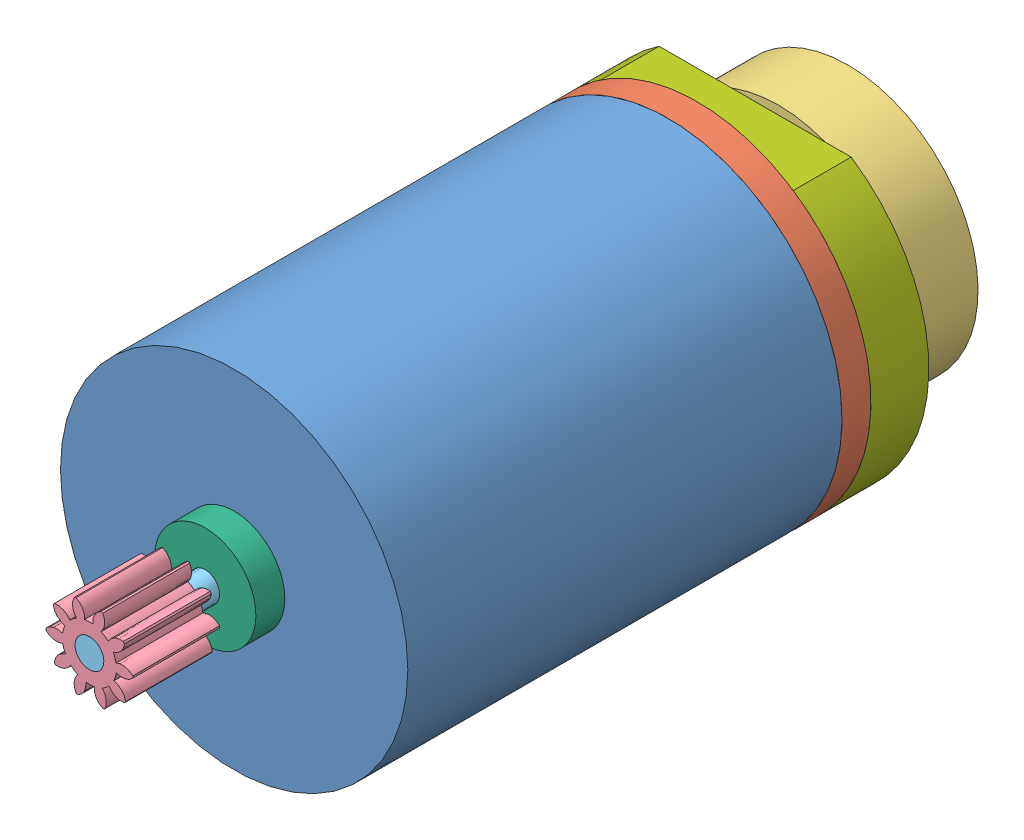
SolidWorks assembly Motor, configuration Default. Lengths in mm.
Overall size (14.57 14.57 26.2).
7 component instances, 7 part files, 14 mates.
Components (placement in the parent):
- body-1: body [Default] at (7.0099 12.5359 7.5707) size (12 12 15)
- back cover-1: back cover [Default] at (7.0099 12.5359 6.5707) x (0.969512 0.245046 0) z (0 0 1) size (12 12 1)
- magnet-1: magnet [Default] at (7.0099 12.5359 1.3707) x (0.345341 -0.938477 0) z (0 0 1) size (9 9 2.4)
- spur gear_am-1: spur gear_am [Metric - Spur gear 0.25M 10T 20PA 3FW ---S10N75H50L1N] at (7.0099 12.5359 24.5707) x (0 0 1) z (-0.822446 0.568843 0) size (3 2.87 3)
- rod-1: rod [Default] at (7.0099 12.5359 1.3707) x (0.869463 0.493997 0) z (0 0 1) size (1 1 26.2)
- brass bearing-1: brass bearing [Default] at (7.0099 12.5359 22.5707) x (0.921198 0.389094 0) z (0 0 1) size (3.5 3.5 1)
- PCB-1: PCB [Default] at (7.0099 12.5359 4.5707) size (12 10.5 2)
Mates (geometry in assembly coordinates):
- Concentric1: concentric aligned: cylinder of body-1 through (7.0099 12.5359 22.5707) axis (0 0 -1) radius 6; cylinder of rod-1 through (7.0099 12.5359 27.5707) axis (0 0 -1) radius 0.5
- Concentric2: concentric aligned: cylinder of body-1 through (7.0099 12.5359 22.5707) axis (0 0 -1) radius 6; cylinder of back cover-1 through (7.0099 12.5359 7.5707) axis (0 0 -1) radius 6
- Concentric3: concentric aligned: cylinder of body-1 through (7.0099 12.5359 22.5707) axis (0 0 -1) radius 6; cylinder of magnet-1 through (7.0099 12.5359 3.7707) axis (0 0 -1) radius 4.5
- Coincident1: coincident anti-aligned: plane of body-1 through (7.0099 12.5359 7.5707) normal (0 0 -1); plane of back cover-1 through (7.0099 12.5359 7.5707) normal (0 0 1)
- Distance1: distance = 5 mm aligned: plane of rod-1 through (7.0099 12.5359 27.5707) normal (0 0 1); plane of body-1 through (7.0099 12.5359 22.5707) normal (0 0 1)
- Concentric4: concentric aligned: cylinder of body-1 through (7.0099 12.5359 22.5707) axis (0 0 -1) radius 6; cylinder of spur gear_am-1 through (7.0099 12.5359 74.5708) axis (0 0 -1) radius 0.5
- Coincident2: coincident aligned: plane of magnet-1 through (7.0099 12.5359 1.3707) normal (0 0 -1); plane of rod-1 through (7.0099 12.5359 1.3707) normal (0 0 -1)
- Coincident3: coincident aligned: plane of spur gear_am-1 through (7.0099 12.5359 27.5707) normal (0 0 1); plane of rod-1 through (7.0099 12.5359 27.5707) normal (0 0 1)
- Concentric5: concentric aligned: cylinder of body-1 through (7.0099 12.5359 22.5707) axis (0 0 -1) radius 6; cylinder of brass bearing-1 through (7.0099 12.5359 23.5707) axis (0 0 -1) radius 1.75
- Coincident4: coincident anti-aligned: plane of body-1 through (7.0099 12.5359 22.5707) normal (0 0 1); plane of brass bearing-1 through (7.0099 12.5359 22.5707) normal (0 0 -1)
- Concentric6: concentric aligned: cylinder of body-1 through (7.0099 12.5359 22.5707) axis (0 0 -1) radius 6; cylinder of PCB-1 through (7.0099 12.5359 6.5707) axis (0 0 -1) radius 6
- Coincident5: coincident anti-aligned: plane of back cover-1 through (7.0099 12.5359 6.5707) normal (0 0 -1); plane of PCB-1 through (7.0099 12.5359 6.5707) normal (0 0 1)
- Parallel1: parallel aligned: plane of PCB-1 through (7.0099 17.5359 4.5707) normal (0 1 0)
- Lock1: lock: unknown of magnet-1; unknown of spur gear_am-1
